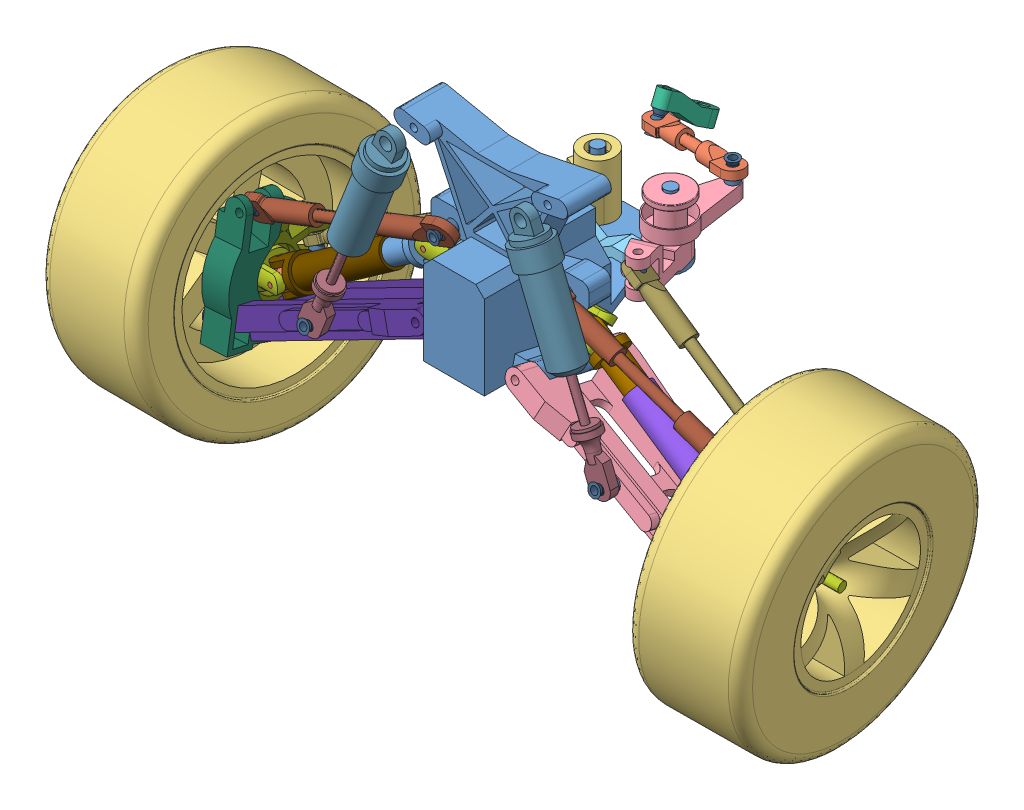
SolidWorks assembly Front Stock, configuration Default. Lengths in mm.
Overall size (360.46 224.44 224.44).
56 component instances, 25 part files, 33 mates.
Components (placement in the parent):
- Center Fixture_fore-1: Center Fixture_fore [Default] at (132.0963 115.607 70.2438) size (71.3 79.35 82.88)
- Front Left Assy-2: Front Left Assy [Default] at (115.6995 12.502 93.2873) x (-0.188438 -0.974631 -0.120768) z (0.06419 -0.134931 0.988774) size (159.16 145.96 148.12) (flexible)
  - U Joint Ball-1: U Joint Ball [Default] at (-80.4711 97.646 -22.7171) x (0.819401 -0.239204 -0.520925) z (0.548822 0.065067 0.833403) size (13.5 7.5 13.5)
  - Wheel-2: Wheel [Default] at (-82.8764 122.5274 -23.0758) x (0.890486 0.092503 0.445509) z (-0.444723 -0.030086 0.895162) size (110 44.74 110)
  - Suspension Plate_L-1: Suspension Plate_L [Front] at (-57.5529 116.9757 -33.5071) x (0.196428 0.960564 0.196805) z (-0.328854 -0.124552 0.936131) size (100 11 45)
  - Suspension Mount Fore-Left-1: Suspension Mount Fore-Left [Default] at (-67.4795 111.9243 3.4604) x (-0.328854 -0.124552 0.936131) z (0.143925 -0.986295 -0.080666) size (30.03 49.25 12.85)
  - SteeringControlArm-Left-1: SteeringControlArm-Left [Default] at (-81.0003 103.1199 -22.796) x (0.096209 -0.995258 0.014347) z (-0.452979 -0.030944 0.890984) size (16.43 32 34)
  - U Joint A - Wheel_fore-1: U Joint A - Wheel_fore [Default] at (-82.6839 120.5369 -23.0471) x (0.548822 0.065067 0.833403) z (-0.096209 0.995258 -0.014347) size (13.86 13.5 42.5)
  - Slip Yoke_fore-1: Slip Yoke_fore [Default] at (-44.9291 100.2808 -5.6439) x (-0.819401 0.239204 0.520925) z (-0.363784 -0.919313 -0.150084) size (13.5 13.5 79.45) (flexible)
    - U Joint A - Outer Yoke_Rear-1: U Joint A - Outer Yoke_Rear [Default] at (19.5991 29.2682 47.9142) size (13.5 13.5 54.5)
    - U Joint B - Inner Yoke_Rear-1: U Joint B - Inner Yoke_Rear [Default] at (19.5991 29.2682 58.3615) x (-1 0 0) z (0 0 -1) size (13.5 13.5 58.5)
  - TurnbuckleAssy_fore-1: TurnbuckleAssy_fore [Default] at (-89.7432 30.7611 -29.4767) x (0.985222 -0.146582 0.08861) z (0.136949 0.984839 0.106471) size (10 9.73 91) (flexible)
    - Turnbuckle Ball Spacer-1: Turnbuckle Ball Spacer [Default] at (-25.0236 -4.6638 -14.0869) x (0.01847 0.999827 -0.002083) z (0.415422 -0.005779 0.909611) size (8.25 5.2 5.2)
    - Turnbuckle Bar_fore-1: Turnbuckle Bar_fore [Default] at (-25.0236 -4.6638 26.4131) size (10 7 91)
    - Turnbuckle Ball Spacer-2: Turnbuckle Ball Spacer [Default] at (-25.0236 -4.6638 66.9131) x (0.222786 0.972491 0.068028) z (0.485429 -0.17118 0.857354) size (8.25 5.2 5.2)
  - Steering TurnbuckleAssy_fore-1: Steering TurnbuckleAssy_fore [Default] at (-92.6897 43.8107 -80.0957) x (0.498059 -0.01314 -0.867043) z (0.324163 0.930213 0.172113) size (10 11.02 100) (flexible)
    - Turnbuckle Ball Spacer-1: Turnbuckle Ball Spacer [Default] at (-25.0236 -4.6638 -18.5869) x (0.366087 -0.781461 0.505271) z (-0.308737 0.410217 0.85814) size (8.25 5.2 5.2)
    - Steering turnbuckle Bar_fore-1: Steering turnbuckle Bar_fore [Default] at (-25.0236 -4.6638 26.4131) size (10 7 100)
    - Turnbuckle Ball Spacer-2: Turnbuckle Ball Spacer [Default] at (-25.0236 -4.6638 71.4131) x (-0.046755 0.891197 -0.451201) z (-0.990544 0.01696 0.136142) size (8.25 5.2 5.2)
  - Suspension_fore-1: Suspension_fore [Default] at (-136.4781 12.3434 -45.0318) x (-0.54222 0.840193 0.00854) z (0.831512 0.535102 0.149177) size (15.7 15.7 94.11) (flexible)
    - Suspension Inner_fore-1: Suspension Inner_fore [Default] at (14.4288 30.3657 20.0829) size (10 10 58)
    - Suspension Outer_fore-1: Suspension Outer_fore [Default] at (14.4288 30.3657 36.9918) x (0 -1 0) z (0 0 -1) size (15.7 15.7 53)
    - Turnbuckle Ball Spacer-1: Turnbuckle Ball Spacer [Default] at (14.4288 30.3657 74.3221) x (0.081658 0.976296 -0.200445) z (0.156428 -0.211178 -0.964849) size (8.25 5.2 5.2)
- Front Right Assy-2: Front Right Assy [Default] at (-87.7279 68.655 139.5731) x (0.902025 0.283461 0.325579) z (-0.009259 0.766736 -0.641896) size (171.56 161.18 154.94) (flexible)
  - Wheel-1: Wheel [Default] at (71.3156 90.8638 45.9989) x (0.198078 -0.609621 0.767546) z (0.237185 -0.72998 -0.640993) size (110 44.74 110)
  - Suspension_fore-1: Suspension_fore [Default] at (158.4314 75.2245 116.0738) x (0.735123 0.612814 -0.28992) z (-0.594636 0.377481 -0.70987) size (15.7 15.7 95) (flexible)
    - Suspension Inner_fore-1: Suspension Inner_fore [Default] at (14.4288 30.3657 20.0829) size (10 10 58)
    - Suspension Outer_fore-1: Suspension Outer_fore [Default] at (14.4288 30.3657 36.0829) x (0 -1 0) z (0 0 -1) size (15.7 15.7 53)
    - Turnbuckle Ball Spacer-1: Turnbuckle Ball Spacer [Default] at (14.4288 30.3657 74.3221) x (0.079409 -0.976296 0.201346) z (0.993139 0.060091 -0.100316) size (8.25 5.2 5.2)
  - Suspension Mount Fore-Right-1: Suspension Mount Fore-Right [Default] at (85.4769 87.8419 16.8813) x (0.379213 -0.80245 -0.460728) z (0.912064 0.408101 0.039907) size (30.03 49.25 12.85)
  - SteeringControlArm-Right-1: SteeringControlArm-Right [Default] at (89.8612 96.8897 45.9989) x (0.951057 0.309017 0) z (0.289297 -0.890363 -0.351512) size (16.43 32 34)
  - Suspension Plate_R-1: Suspension Plate_R [Front] at (82.2805 93.2668 23.251) x (-0.903592 -0.213902 -0.37117) z (-0.379213 0.80245 0.460728) size (100 11 45)
  - U Joint A - Outer Yoke_fore-1: U Joint A - Outer Yoke_fore [Default] at (121.8548 100.0536 59.4752) x (-0.298504 -0.682665 0.666982) z (0.892093 0.04881 0.449208) size (13.5 13.5 54.5)
  - U Joint A - Wheel_fore-1: U Joint A - Wheel_fore [Default] at (73.2177 91.4819 45.9989) x (0.237185 -0.72998 -0.640993) z (-0.951057 -0.309017 0) size (13.86 13.5 42.5)
  - U Joint B - Inner Yoke_fore-1: U Joint B - Inner Yoke_fore [Default] at (131.612 100.5874 64.3884) x (0.298504 0.682665 -0.666982) z (-0.892093 -0.04881 -0.449208) size (13.5 13.5 58.5)
  - U Joint Ball-1: U Joint Ball [Default] at (95.092 98.5893 45.9989) x (-0.237185 0.72998 0.640993) z (-0.298504 -0.682665 0.666982) size (13.5 7.5 13.5)
  - Steering TurnbuckleAssy_fore-1: Steering TurnbuckleAssy_fore [Default] at (136.2922 140.9754 99.2135) x (-0.33805 0.784746 0.519515) z (-0.898974 -0.105893 -0.425009) size (10 10.82 100.27) (flexible)
    - Turnbuckle Ball Spacer-1: Turnbuckle Ball Spacer [Default] at (-25.0236 -4.6638 -18.5869) x (-0.1495 -0.841167 -0.5197) z (0.688653 0.288582 -0.66519) size (8.25 5.2 5.2)
    - Steering turnbuckle Bar_fore-1: Steering turnbuckle Bar_fore [Default] at (-25.0236 -4.6638 26.4131) size (10 7 100)
    - Turnbuckle Ball Spacer-2: Turnbuckle Ball Spacer [Default] at (-25.0236 -4.6638 71.4131) x (-0.187295 0.867869 0.460135) z (-0.973767 -0.22566 0.029258) size (8.25 5.2 5.2)
  - TurnbuckleAssy_fore-1: TurnbuckleAssy_fore [Default] at (113.9635 56.2923 70.4531) x (0.084482 -0.912141 0.401076) z (0.94072 0.20571 0.269683) size (10.57 10.64 91) (flexible)
    - Turnbuckle Ball Spacer-1: Turnbuckle Ball Spacer [Default] at (-25.0236 -4.6638 -14.0869) x (0.579197 0.812396 0.067411) z (0.40669 -0.216299 -0.887591) size (8.25 5.2 5.2)
    - Turnbuckle Bar_fore-1: Turnbuckle Bar_fore [Default] at (-25.0236 -4.6638 26.4131) size (10 7 91)
    - Turnbuckle Ball Spacer-2: Turnbuckle Ball Spacer [Default] at (-25.0236 -4.6638 66.9131) x (-0.4033 -0.915017 0.009642) z (0.752376 -0.337575 -0.565662) size (8.25 5.2 5.2)
- Linkage TurnbuckleAssy_fore-1: Linkage TurnbuckleAssy_fore [Default] at (100.81 121.2118 16.4535) x (-0.161829 0.072069 0.984184) z (0.980915 0.120675 0.152455) size (9.12 9.69 46.4)
  - Turnbuckle Ball Spacer-1: Turnbuckle Ball Spacer [Default] at (-25.0236 -4.6638 7.6131) x (0.416171 0.905102 0.087129) z (-0.208661 0.001798 0.977986) size (8.25 5.2 5.2)
  - Linkage Turnbuckle Bar_fore-1: Linkage Turnbuckle Bar_fore [Default] at (-25.0236 -4.6638 26.4131) size (8.8 7 46.4)
  - Turnbuckle Ball Spacer-2: Turnbuckle Ball Spacer [Default] at (-25.0236 -4.6638 45.2131) x (-0.072069 0.990072 -0.120675) z (-0.090577 0.113993 0.989344) size (8.25 5.2 5.2)
- LinkagePost-1: LinkagePost [Default] at (117.0963 110.607 22.2438) x (-0.370792 0 0.928716) z (0 1 0) size (35.88 16.5 22.85)
- LinkagePostwspring-1: LinkagePostwspring [Default] at (147.0963 110.607 22.2438) x (0.386739 0 0.922189) z (0 1 0) size (53.33 23.25 23)
- Post Linkage-1: Post Linkage [Default] at (117.4775 110.607 37.4706) x (1 0 0.000146) z (-0.000146 0 1) size (38 10 8.5)
- Servo Horn-1: Servo Horn [Default] at (113.0687 125.9078 -26.6497) x (0.150406 -0.486998 -0.860355) z (-0.981834 -0.175401 -0.072359) size (24 9 9.5)
- STD U joint-1: STD U joint [Default] at (155.0963 115.607 70.2438) x (0 -0.654169 0.756349) z (-1 0 0) size (13.5 13.5 12.5)
- STD U joint-2: STD U joint [Default] at (109.0963 115.607 70.2438) x (0 -0.062545 -0.998042) z (1 0 0) size (13.5 13.5 12.5)
- U Joint Ball-1: U Joint Ball [Default] at (100.0963 115.607 70.2438) x (-0.570061 0.819994 -0.051387) z (0 0.062545 0.998042) size (13.5 7.5 13.5)
- U Joint Ball-2: U Joint Ball [Default] at (164.0963 115.607 70.2438) x (0.42226 0.685611 0.592987) z (0 -0.654169 0.756349) size (13.5 7.5 13.5)
Mates (geometry in assembly coordinates):
- Coincident15: coincident anti-aligned: plane of Center Fixture_fore-1 through (152.5963 94.8265 55.0527) normal (0 -0.21644 -0.976296); plane of Front Right Assy-2/Suspension Plate_R-1 through (113.5015 100.0266 53.8998) normal (0 0.21644 0.976296)
- Concentric12: concentric aligned: cylinder of Center Fixture_fore-1 through (111.5963 101.3196 84.3415) axis (0 -0.21644 -0.976296) radius 1.5; cylinder of Front Right Assy-2/Suspension Plate_R-1 through (111.5963 102.9429 91.6638) axis (0 -0.21644 -0.976296) radius 1.575
- Coincident16: coincident anti-aligned: plane of Center Fixture_fore-1 through (152.5963 94.8265 55.0527) normal (0 -0.21644 -0.976296); plane of Front Left Assy-2/Suspension Plate_L-1 through (150.5245 99.9655 53.9134) normal (0 0.21644 0.976296)
- Concentric13: concentric anti-aligned: cylinder of Center Fixture_fore-1 through (152.5963 101.3196 84.3415) axis (0 -0.21644 -0.976296) radius 1.5; circle of Front Left Assy-2/Suspension Plate_L-1
- Concentric15: concentric aligned: circle of Center Fixture_fore-1; circle of Front Right Assy-2/Suspension_fore-1/Suspension Outer_fore-1
- Coincident17: coincident anti-aligned: circle of Center Fixture_fore-1; circle of Front Right Assy-2/TurnbuckleAssy_fore-1/Turnbuckle Ball Spacer-2
- Concentric16: concentric aligned: circle of Center Fixture_fore-1; cylinder of Front Left Assy-2/Suspension_fore-1/Suspension Outer_fore-1 through (159.5963 165.607 92.5228) axis (0 0 1) radius 2.5
- Coincident18: coincident anti-aligned: circle of Center Fixture_fore-1; circle of Front Left Assy-2/TurnbuckleAssy_fore-1/Turnbuckle Ball Spacer-1
- Concentric17: concentric aligned: cylinder of Center Fixture_fore-1 through (147.0963 134.607 22.2438) axis (0 -1 0) radius 2.5; cylinder of LinkagePostwspring-1 through (147.0963 113.857 22.2438) axis (0 -1 0) radius 4
- Coincident19: coincident anti-aligned: plane of Center Fixture_fore-1 through (144.5963 110.607 31.1249) normal (0 1 0); plane of LinkagePostwspring-1 through (147.0963 110.607 22.2438) normal (0 -1 0)
- Coincident20: coincident anti-aligned: plane of Center Fixture_fore-1 through (144.5963 110.607 31.1249) normal (0 1 0); plane of LinkagePost-1 through (117.0963 110.607 22.2438) normal (0 -1 0)
- Concentric18: concentric aligned: cylinder of Center Fixture_fore-1 through (117.0963 134.607 22.2438) axis (0 -1 0) radius 2.5; cylinder of LinkagePost-1 through (117.0963 113.857 22.2438) axis (0 -1 0) radius 4
- Coincident21: coincident anti-aligned: plane of LinkagePost-1 through (117.4775 116.607 37.4706) normal (0 1 0); plane of Post Linkage-1 through (117.4784 116.607 31.7206) normal (0 -1 0)
- Concentric19: concentric aligned: circle of LinkagePost-1; circle of Post Linkage-1
- Concentric20: concentric anti-aligned: circle of LinkagePostwspring-1; circle of Post Linkage-1
- Coincident22: coincident anti-aligned: circle of Front Right Assy-2/Steering TurnbuckleAssy_fore-1/Turnbuckle Ball Spacer-1; circle of LinkagePost-1
- Concentric23: concentric aligned: circle of Front Left Assy-2/Steering TurnbuckleAssy_fore-1/Turnbuckle Ball Spacer-1; circle of LinkagePostwspring-1
- Coincident23: coincident anti-aligned: plane of Front Left Assy-2/Steering TurnbuckleAssy_fore-1/Turnbuckle Ball Spacer-1 through (156.7648 116.607 45.2985) normal (0 -1 0); plane of LinkagePostwspring-1 through (144.1516 116.607 46.2506) normal (0 1 0)
- Coincident24: coincident anti-aligned: plane of Center Fixture_fore-1 through (109.0963 115.607 70.2438) normal (-1 0 0); plane of STD U joint-2 through (109.0963 115.607 70.2438) normal (1 0 0)
- Concentric25: concentric anti-aligned: cylinder of Center Fixture_fore-1 through (155.0963 115.607 70.2438) axis (-1 0 0) radius 5; cylinder of STD U joint-2 through (106.0963 115.607 70.2438) axis (1 0 0) radius 6.75
- Coincident25: coincident anti-aligned: plane of Center Fixture_fore-1 through (155.0963 115.607 70.2438) normal (1 0 0); plane of STD U joint-1 through (155.0963 115.607 70.2438) normal (-1 0 0)
- Concentric26: concentric aligned: cylinder of Center Fixture_fore-1 through (155.0963 115.607 70.2438) axis (-1 0 0) radius 5; cylinder of STD U joint-1 through (158.0963 115.607 70.2438) axis (-1 0 0) radius 6.75
- Concentric27: concentric aligned: cylinder of STD U joint-2 through (100.0963 116.0292 76.9806) axis (0 -0.062545 -0.998042) radius 1; cylinder of U Joint Ball-1 through (100.0963 116.0292 76.9806) axis (0 -0.062545 -0.998042) radius 1
- Tangent1: tangent anti-aligned: plane of STD U joint-2 through (96.5963 118.8656 66.2822) normal (0 0.062545 0.998042); sphere of U Joint Ball-1
- Concentric28: concentric anti-aligned: cylinder of Front Right Assy-2/U Joint B - Inner Yoke_fore-1 through (96.2484 121.142 69.8969) axis (0.570061 -0.819994 0.051387) radius 1; cylinder of U Joint Ball-1 through (103.9443 110.072 70.5907) axis (-0.570061 0.819994 -0.051387) radius 1
- Tangent3: tangent anti-aligned: plane of Front Right Assy-2/U Joint B - Inner Yoke_fore-1 through (105.0985 114.7354 73.8189) normal (-0.570061 0.819994 -0.051387); sphere of U Joint Ball-1
- Tangent4: tangent anti-aligned: plane of STD U joint-1 through (167.5963 115.4129 65.1179) normal (0 -0.654169 0.756349); sphere of U Joint Ball-2
- Coincident27: coincident aligned: cylinder of STD U joint-1 through (164.0963 120.0226 65.1384) axis (0 -0.654169 0.756349) radius 1; circle of U Joint Ball-2
- Tangent6: tangent anti-aligned: plane of Front Left Assy-2/Slip Yoke_fore-1/U Joint B - Inner Yoke_Rear-1 through (161.5577 118.3518 75.202) normal (-0.42226 -0.685611 -0.592987); sphere of U Joint Ball-2
- Concentric29: concentric anti-aligned: cylinder of Front Left Assy-2/Slip Yoke_fore-1/U Joint B - Inner Yoke_Rear-1 through (166.9466 120.2349 74.2465) axis (-0.42226 -0.685611 -0.592987) radius 1; cylinder of U Joint Ball-2 through (161.2461 110.9791 66.2411) axis (0.42226 0.685611 0.592987) radius 1
- LimitDistance1: limit distance = -0.1318 mm: point of Post Linkage-1; plane of Center Fixture_fore-1 through (132.0963 115.607 70.2438) normal (1 0 0)
- Coincident28: coincident anti-aligned: circle of Linkage TurnbuckleAssy_fore-1/Turnbuckle Ball Spacer-2; circle of LinkagePostwspring-1
- Coincident29: coincident anti-aligned: circle of Linkage TurnbuckleAssy_fore-1/Turnbuckle Ball Spacer-1; circle of Servo Horn-1
